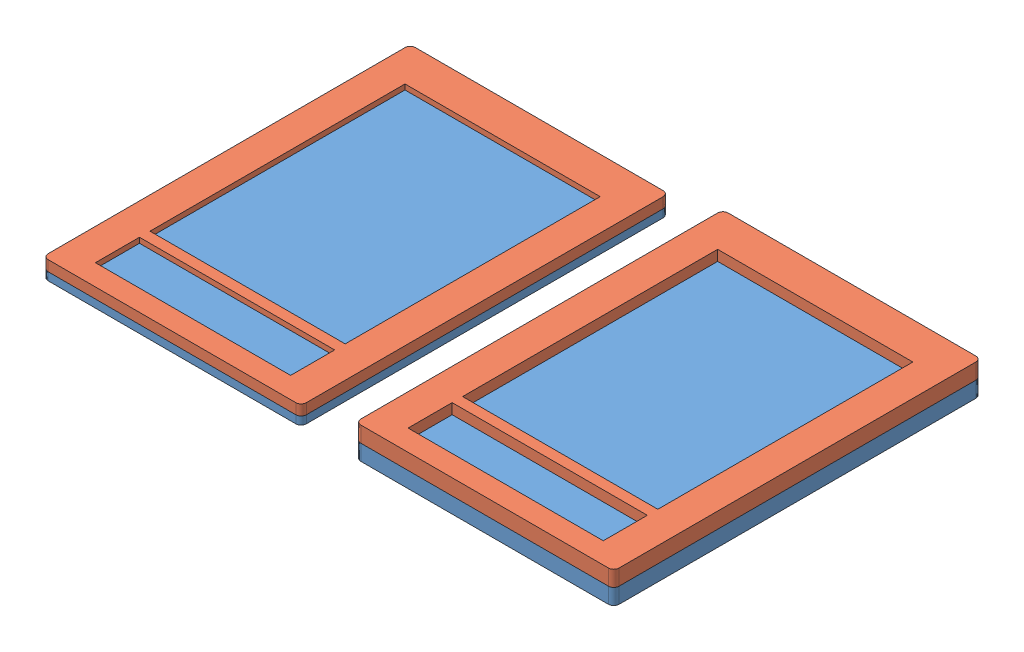
SolidWorks assembly InstaxFrameAssembly, configuration Default. Lengths in mm.
Overall size (138.16 7.62 88.9).
4 component instances, 2 part files, 15 mates.
Components (placement in the parent):
- BaseRevD-1: BaseRevD [Default] at (-21.2693 74.0105 46.2434) size (62.48 3.81 88.9)
- BaseRevD-2: BaseRevD [Slim] at (-96.9409 74.0105 46.2434) size (62.48 1.91 88.9)
- CoverC-2: CoverC [Slim] at (-96.4329 78.4555 46.2434) x (-1 0 0) z (0 0 1) size (62.48 3.81 88.9)
- CoverC-3: CoverC [Default] at (-20.7613 81.6305 46.2434) x (-1 0 0) z (0 0 1) size (62.48 6.35 88.9)
Mates (geometry in assembly coordinates):
- Coincident4: coincident anti-aligned: plane of Base-1 through (56.8164 49.0433 56.5557) normal (0 1 0); plane of Cover-1 through (57.3244 49.0433 56.5557) normal (0 -1 0)
- Coincident5: coincident aligned: plane of Base-1 through (56.8164 49.0433 102.6567) normal (0 0 1); plane of Cover-1 through (57.3244 50.3133 102.6567) normal (0 0 1)
- Coincident6: coincident aligned: plane of Base-1 through (88.3124 49.0433 56.5557) normal (1 0 0); plane of Cover-1 through (88.3124 50.3133 56.5557) normal (1 0 0)
- Coincident7: coincident aligned: plane of BaseRevD-1 through (-52.2573 77.8205 46.2434) normal (-1 0 0); plane of CoverC-1 through (-52.2573 79.0905 49.5454) normal (-1 0 0)
- Coincident8: coincident aligned: plane of BaseRevD-1 through (-21.2693 77.8205 92.3444) normal (0 0 1); plane of CoverC-1 through (-21.2693 79.0905 92.3444) normal (0 0 1)
- Coincident9: coincident anti-aligned: plane of BaseRevD-1 through (-21.2693 77.8205 46.2434) normal (0 1 0); plane of CoverC-1 through (-21.2693 77.8205 49.5454) normal (0 -1 0)
- Coincident10: coincident anti-aligned: plane of BaseRevD-1 through (-21.2693 77.8205 46.2434) normal (0 1 0); plane of CoverC-3 through (-20.7613 77.8205 46.2434) normal (0 -1 0)
- Coincident13: coincident aligned: plane of BaseRevD-1 through (10.2267 77.8205 46.2434) normal (1 0 0); plane of CoverC-3 through (10.2267 79.0905 46.2434) normal (1 0 0)
- Coincident14: coincident aligned: plane of BaseRevD-2 through (-65.4449 75.9155 46.2434) normal (1 0 0); plane of CoverC-2 through (-65.4449 77.1855 46.2434) normal (1 0 0)
- Coincident15: coincident aligned: plane of BaseRevD-2 through (-96.9409 75.9155 92.3444) normal (0 0 1); plane of CoverC-2 through (-96.4329 77.1855 92.3444) normal (0 0 1)
- Coincident16: coincident aligned: plane of BaseRevD-1 through (-21.2693 77.8205 92.3444) normal (0 0 1); plane of CoverC-3 through (-20.7613 79.0905 92.3444) normal (0 0 1)
- Parallel1: parallel aligned: plane of BaseRevD-1 through (-21.2693 77.8205 92.3444) normal (0 0 1); plane of BaseRevD-2 through (-96.9409 75.9155 92.3444) normal (0 0 1)
- Coincident21: coincident anti-aligned: plane of BaseRevD-2 through (-96.9409 75.9155 46.2434) normal (0 1 0); plane of CoverC-2 through (-96.4329 75.9155 46.2434) normal (0 -1 0)
- Coincident22: coincident aligned: plane of BaseRevD-1 through (-21.2693 74.0105 46.2434) normal (0 -1 0); plane of BaseRevD-2 through (-96.9409 74.0105 46.2434) normal (0 -1 0)
- Coincident23: coincident aligned: plane of CoverC-2 through (-96.4329 77.1855 92.3444) normal (0 0 1); plane of CoverC-3 through (-20.7613 79.0905 92.3444) normal (0 0 1)
